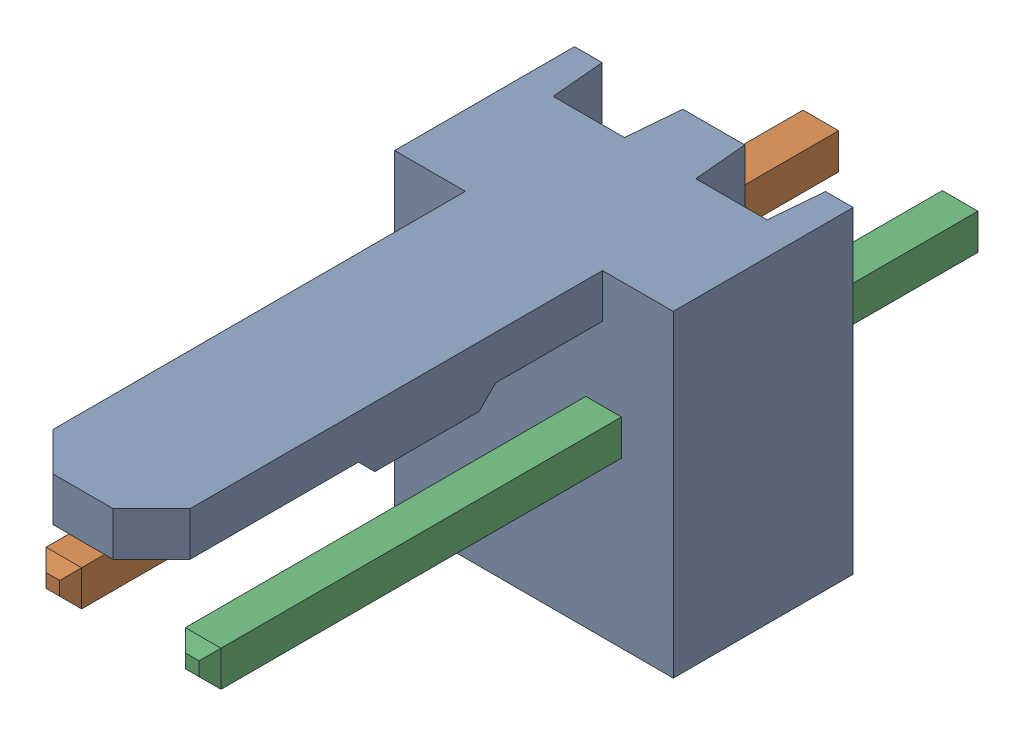
SolidWorks assembly Molex PCB 2 pin v2 (5), configuration Default. Lengths in mm.
Overall size (5.08 5.79 14.92).
3 component instances, 2 part files, 0 mates.
Components (placement in the parent):
- BASE9710016-1: BASE9710016 [Default] at (2.54 2.895 -8.22) size (5.08 5.79 11.5)
- PINO9710016-1: PINO9710016 [Default] at (1.27 3.325 -0.72) size (0.65 0.65 14.2)
- PINO9710016-2: PINO9710016 [Default] at (3.81 3.325 -0.72) size (0.65 0.65 14.2)
